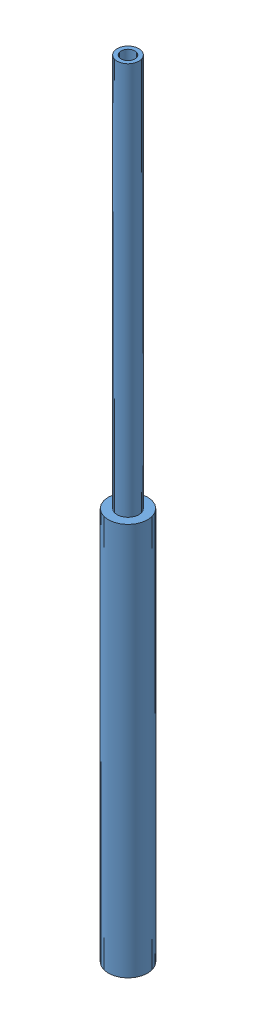
SolidWorks assembly ThreadedRodTurnTool, configuration Default. Lengths in mm.
Overall size (5 100 5).
2 component instances, 2 part files, 3 mates.
Components (placement in the parent):
- ThreadedRodTool-1: ThreadedRodTool [Default] at (-27.2189 -58.1107 0) size (5 100 5)
- drive_threaded_rod_70mm-1: drive_threaded_rod_70mm [Default] at (-27.2189 -31.6107 0) x (0.964488 0 0.264127) z (-0.264127 0 0.964488) size (1.64 70.49 1.64)
Mates (geometry in assembly coordinates):
- Concentric1: concentric aligned: circle of ThreadedRodTool-1; circle of drive_threaded_rod_70mm-1
- Distance1: distance = 3.5 mm aligned: plane of ThreadedRodTool-1 through (-27.2189 41.8893 0) normal (0 1 0); plane of drive_threaded_rod_70mm-1 through (-27.2189 38.3893 0) normal (0 1 0)
- Angle1: planar angle = 0.785398 rad aligned: plane of drive_threaded_rod_70mm-1 through (-27.7388 36.3893 -0.52) normal (0.707107 0 -0.707107); plane of assembly
